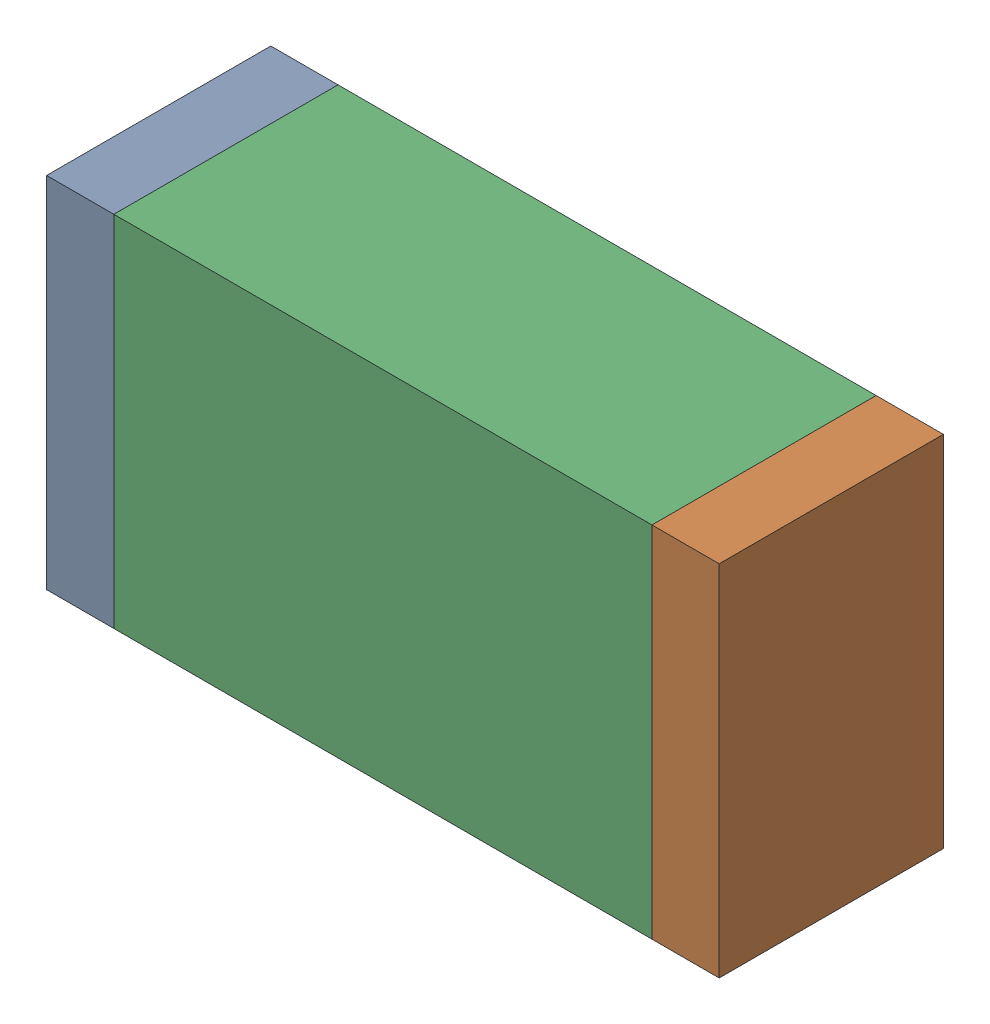
SolidWorks assembly R5, configuration Default. Lengths in mm.
Overall size (1.5 0.8 0.5).
6 component instances, 2 part files, 0 mates.
Components (placement in the parent):
- 836752496-1: 836752496 [Default] at (135.875 32.55 0) size (0.15 0.8 0.5)
  - Extruded_2-1: Extruded_2 [Default] at origin size (0.15 0.8 0.5)
- 836752496-2: 836752496 [Default] at (137.225 32.55 0) size (0.15 0.8 0.5)
  - Extruded_2-1: Extruded_2 [Default] at origin size (0.15 0.8 0.5)
- 836752368-1: 836752368 [Default] at (136.55 32.55 0) size (1.2 0.8 0.5)
  - Extruded-1: Extruded [Default] at origin size (1.2 0.8 0.5)
